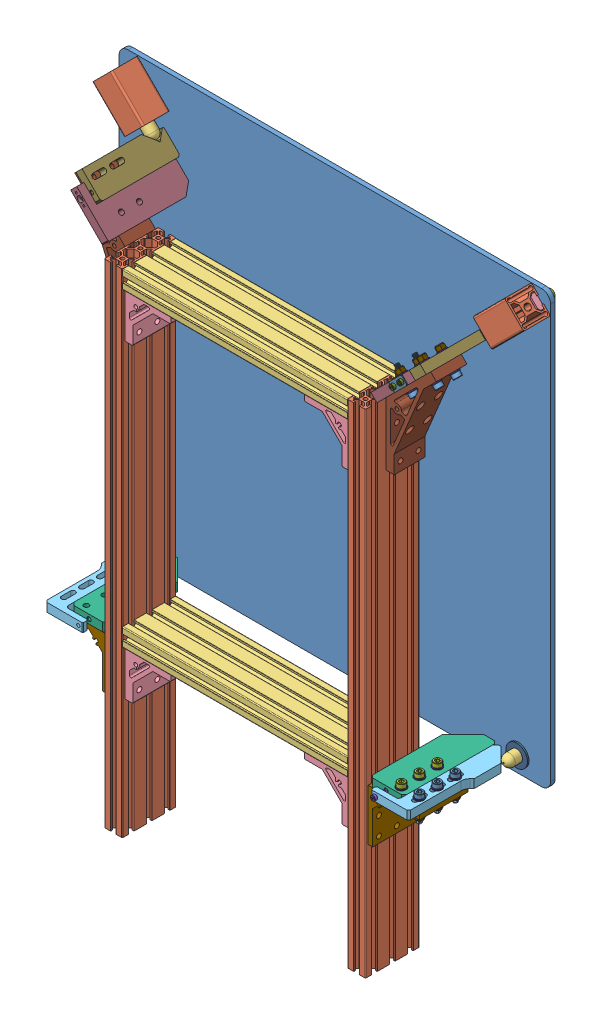
SolidWorks assembly Bed2-MountAssembly, configuration Default. Lengths in mm.
Overall size (480 651.24 139.8).
101 component instances, 28 part files, 132 mates.
Components (placement in the parent):
- Bed2-Assembly-1: Bed2-Assembly [Default] at origin size (480 480 46.46)
  - Bed2_5mm-1: Bed2_5mm [Default] at origin size (480 480 5)
  - HFS6_3030_50_LTP-1: HFS6_3030_50_LTP [Default] at (194.0381 194.0381 20) x (0.707107 -0.707107 0) z (-0.707107 -0.707107 0) size (30 30 50)
  - HFS6_3030_50_LTP-2: HFS6_3030_50_LTP [Default] at (-194.0381 194.0381 20) x (0.707107 0.707107 0) z (0.707107 -0.707107 0) size (30 30 50)
  - CJPQNBB8_13-1: CJPQNBB8_13 [Default] at (-194.0381 194.0381 20) x (0.707107 -0.707107 0) z (-0.707107 -0.707107 0) size (31.47 13 13)
  - CJPQNBB8_13-2: CJPQNBB8_13 [Default] at (194.0381 194.0381 20) x (-0.707107 -0.707107 0) z (0.707107 -0.707107 0) size (31.47 13 13)
  - HNTC6-1: HNTC6 [Default] at (-197.5736 197.5736 7) x (0.707107 0.707107 0) z (0 0 1) size (15 16 6.3)
  - HNTC6-2: HNTC6 [Default] at (-213.9106 213.9106 7) x (-0.707107 -0.707107 0) z (0 0 1) size (15 16 6.3)
  - HNTC6-3: HNTC6 [Default] at (-225.8579 225.8579 7) x (-0.707107 -0.707107 0) z (0 0 1) size (15 16 6.3)
  - HNTC6-4: HNTC6 [Default] at (213.9106 213.9106 7) x (-0.707107 0.707107 0) z (0 0 1) size (15 16 6.3)
  - HNTC6-5: HNTC6 [Default] at (197.5736 197.5736 7) x (0.707107 -0.707107 0) z (0 0 1) size (15 16 6.3)
  - HNTC6-6: HNTC6 [Default] at (225.8579 225.8579 7) x (-0.707107 0.707107 0) z (0 0 1) size (15 16 6.3)
  - 1-4_silicone_99604A115-1: 1-4_silicone_99604A115 [99604A115] at (-197.5736 197.5736 0) size (15.88 15.88 2.36)
  - 1-4_silicone_99604A115-2: 1-4_silicone_99604A115 [99604A115] at (225.8579 225.8579 0) size (15.88 15.88 2.36)
  - 1-4_silicone_99604A115-3: 1-4_silicone_99604A115 [99604A115] at (-225.8579 225.8579 0) size (15.88 15.88 2.36)
  - 1-4_silicone_99604A115-4: 1-4_silicone_99604A115 [99604A115] at (197.5736 197.5736 0) size (15.88 15.88 2.36)
  - 1-4_silicone_99604A115-5: 1-4_silicone_99604A115 [99604A115] at (213.9106 213.9106 0) size (15.88 15.88 2.36)
  - 1-4_silicone_99604A115-6: 1-4_silicone_99604A115 [99604A115] at (-213.9106 213.9106 0) size (15.88 15.88 2.36)
  - M6_ss_93475A250-1: M6_ss_93475A250 [93475A250] at (-197.5736 197.5736 -2.3622) size (12 12 1.4)
  - M6_ss_93475A250-2: M6_ss_93475A250 [93475A250] at (213.9106 213.9106 -2.3622) size (12 12 1.4)
  - M6_ss_93475A250-3: M6_ss_93475A250 [93475A250] at (-213.9106 213.9106 -2.3622) size (12 12 1.4)
  - M6_ss_93475A250-4: M6_ss_93475A250 [93475A250] at (197.5736 197.5736 -2.3622) size (12 12 1.4)
  - M6_ss_93475A250-5: M6_ss_93475A250 [93475A250] at (-225.8579 225.8579 -2.3622) size (12 12 1.4)
  - M6_ss_93475A250-6: M6_ss_93475A250 [93475A250] at (225.8579 225.8579 -2.3622) size (12 12 1.4)
  - M6x18_91292A136-1: M6x18_91292A136 [91292A136] at (-197.5736 197.5736 14.2378) size (10 10 24.53)
  - M6x18_91292A136-2: M6x18_91292A136 [91292A136] at (-213.9106 213.9106 14.2378) size (10 10 24.53)
  - M6x18_91292A136-3: M6x18_91292A136 [91292A136] at (-225.8579 225.8579 14.2378) size (10 10 24.53)
  - M6x18_91292A136-4: M6x18_91292A136 [91292A136] at (197.5736 197.5736 14.2378) size (10 10 24.53)
  - M6x18_91292A136-5: M6x18_91292A136 [91292A136] at (213.9106 213.9106 14.2378) size (10 10 24.53)
  - M6x18_91292A136-6: M6x18_91292A136 [91292A136] at (225.8579 225.8579 14.2378) size (10 10 24.53)
  - CJPQNBB8_13-3: CJPQNBB8_13 [Default] at (-204 -222 6.8) x (0 0 1) z (-0.99919 0.040233 0) size (31.47 13 13)
  - CJPQNBB8_13-4: CJPQNBB8_13 [Default] at (204 -222 6.8) x (0 0 1) z (-0.9546 0.297892 0) size (31.47 13 13)
  - 5-16_silicone_99604A119-1: 5-16_silicone_99604A119 [99604A119] at (-204 -222 0) size (17.46 17.46 2.36)
  - 5-16_silicone_99604A119-2: 5-16_silicone_99604A119 [99604A119] at (204 -222 0) size (17.46 17.46 2.36)
  - Nyloc_M8_flange_ss_92461A300-1: Nyloc_M8_flange_ss_92461A300 [92461A300] at (204 -222 -2.3622) x (1 0 0) z (0 1 0) size (14.2 9.28 14.2)
  - Nyloc_M8_flange_ss_92461A300-2: Nyloc_M8_flange_ss_92461A300 [92461A300] at (-204 -222 -2.3622) x (1 0 0) z (0 1 0) size (14.2 9.28 14.2)
  - M8_fender_ss_91116A160-1: M8_fender_ss_91116A160 [91116A160] at (204 -222 6.8) size (24 24 1.8)
  - M8_fender_ss_91116A160-2: M8_fender_ss_91116A160 [91116A160] at (-204 -222 6.8) size (24 24 1.8)
- HBL135TD5_Z5-1: HBL135TD5_Z5 [Default] at (145.2477 136.7624 76.1924) x (0 0 -1) z (0 -1 0) size (34 55.86 119.5)
  - HBL135TD5_Z5hbl45ts5-1: HBL135TD5_Z5hbl45ts5 [Default] at origin size (34 55.86 119.5)
- V-block_3-1: V-block_3 [Default] x (0 0 -1) z (0.707107 -0.707107 0) size (88.19 30 9.53)
- V-block_3-stage-1: V-block_3-stage [Default] at (3.5355 -3.5355 -1056) x (0 0 -1) z (0.707107 -0.707107 0) size (96.19 50 9.52)
- ScrewRetainer^Bed2-MountAssembly-1: ScrewRetainer^Bed2-MountAssembly [Default] at (0 0 89.1924) x (0.707107 -0.707107 0) z (0 0 1) size (9.53 20 1) (virtual)
- low_M3x20_92855A319-1: low_M3x20_92855A319 [92855A319] at (177.2354 175.4853 100.1924) x (-0.158388 0.987377 0) z (0 0 1) size (5.5 5.5 22.13)
- M3x4_91292A109-1: M3x4_91292A109 [91292A109] at (181.4781 179.728 108.1924) x (-0.923728 -0.383049 0) z (0 0 -1) size (5.5 5.5 7.14)
- M3x4_91292A109-2: M3x4_91292A109 [91292A109] at (172.9928 171.2427 108.1924) x (-0.923728 -0.383049 0) z (0 0 -1) size (5.5 5.5 7.14)
- M5_ss_93475A240-1: M5_ss_93475A240 [93475A240] at (180.3025 186.5604 86.1924) x (0.707107 0.707107 0) z (-0.707107 0.707107 0) size (10 10 0.9)
- M5_ss_93475A240-2: M5_ss_93475A240 [93475A240] at (155.5538 161.8117 86.1924) x (0.707107 0.707107 0) z (-0.707107 0.707107 0) size (10 10 0.9)
- M5_ss_93475A240-3: M5_ss_93475A240 [93475A240] at (155.5538 161.8117 66.1924) x (0.707107 0.707107 0) z (-0.707107 0.707107 0) size (10 10 0.9)
- M5_ss_93475A240-4: M5_ss_93475A240 [93475A240] at (180.3025 186.5604 66.1924) x (0.707107 0.707107 0) z (-0.707107 0.707107 0) size (10 10 0.9)
- M5_ss_93475A240-5: M5_ss_93475A240 [93475A240] at (167.0973 150.2681 66.1924) x (0.707107 0.707107 0) z (0.707107 -0.707107 0) size (10 10 0.9)
- M5_ss_93475A240-6: M5_ss_93475A240 [93475A240] at (194.6745 172.1885 86.1924) x (0.7071 0.7071 0.004344) z (0.707107 -0.707107 0) size (10 10 0.9)
- M5_ss_93475A240-7: M5_ss_93475A240 [93475A240] at (194.6745 172.1885 66.1924) x (0.707107 0.707107 0) z (0.707107 -0.707107 0) size (10 10 0.9)
- M5_ss_93475A240-8: M5_ss_93475A240 [93475A240] at (167.0973 150.2681 86.1924) x (0.707107 0.707107 0) z (0.707107 -0.707107 0) size (10 10 0.9)
- Nyloc_M5_90576A104-1: Nyloc_M5_90576A104 [90576A104] at (155.5538 161.8117 66.1924) x (0.707107 0.707107 0) z (0 0 1) size (8 5.15 9.24)
- Nyloc_M5_90576A104-2: Nyloc_M5_90576A104 [90576A104] at (180.3025 186.5604 66.1924) x (0.707107 0.707107 0) z (0 0 1) size (8 5.15 9.24)
- Nyloc_M5_90576A104-3: Nyloc_M5_90576A104 [90576A104] at (155.5538 161.8117 86.1924) x (0.707107 0.707107 0) z (0 0 1) size (8 5.15 9.24)
- Nyloc_M5_90576A104-4: Nyloc_M5_90576A104 [90576A104] at (180.3025 186.5604 86.1924) x (0.707107 0.707107 0) z (0 0 1) size (8 5.15 9.24)
- M5x25_91292A129-1: M5x25_91292A129 [91292A129] at (176.9968 189.8661 86.1924) x (0.224391 0.224391 0.948313) z (-0.707107 0.707107 0) size (8.5 8.5 30.44)
- M5x25_91292A129-2: M5x25_91292A129 [91292A129] at (176.9968 189.8661 66.1924) x (0.5 0.5 0.707107) z (-0.707107 0.707107 0) size (8.5 8.5 30.44)
- M5x25_91292A129-3: M5x25_91292A129 [91292A129] at (149.4196 167.9458 86.1924) x (0.5 0.5 0.707107) z (-0.707107 0.707107 0) size (8.5 8.5 30.44)
- M5x25_91292A129-4: M5x25_91292A129 [91292A129] at (149.4196 167.9458 66.1924) x (0.5 0.5 0.707107) z (-0.707107 0.707107 0) size (8.5 8.5 30.44)
- StructuralFrame-1^Bed2-MountAssembly-1: StructuralFrame-1^Bed2-MountAssembly [Default<As Machined>] at (0 0 54.1924) size (290.5 548 60) (virtual)
- HBL135TD5_Z5-2: HBL135TD5_Z5 [Default] at (-145.2477 136.7624 76.1924) x (0 0 1) z (0 -1 0) size (34 55.86 119.5)
  - HBL135TD5_Z5hbl45ts5-1: HBL135TD5_Z5hbl45ts5 [Default] at origin size (34 55.86 119.5)
- V-block_3-2: V-block_3 [Default] at (-1.7501 -1.7501 0) x (0 0 -1) z (0.707107 0.707107 0) size (88.19 30 9.53)
- V-block_3-stage-2: V-block_3-stage [Default] at (1.7854 1.7854 -1056) x (0 0 -1) z (0.707107 0.707107 0) size (96.19 50 9.52)
- StructuralFrame-2^Bed2-MountAssembly-1: StructuralFrame-2^Bed2-MountAssembly [Default<As Machined>] at (0 -0.0245 76.1924) size (250.5 364.69 60) (virtual)
- HBLUT5-1: HBLUT5 [Default] at (125.2477 116.7624 86.1924) x (0 0 1) z (0 -1 0) size (54 51 51)
- HBLUT5-2: HBLUT5 [Default] at (-125.2477 116.7624 86.1924) x (0 0 1) z (1 0 0) size (54 51 51)
- HBLUT5-3: HBLUT5 [Default] at (-125.2477 -227.9285 86.1924) x (0 0 -1) z (0 -1 0) size (54 51 51)
- HBLUT5-4: HBLUT5 [Default] at (125.2477 -227.9285 86.1924) x (0 0 1) z (0 -1 0) size (54 51 51)
- V-block_4-1: V-block_4 [Default] at (0 -222 0) x (-1 0 0) z (0 1 0) size (47.16 113.8 9.53)
- V-block_4-stage-1: V-block_4-stage [Default] at (0 -222 0) x (-1 0 0) z (0 1 0) size (38 103.64 9.53)
- M5_ss_93475A240-9: M5_ss_93475A240 [93475A240] at (175.2477 -217.2375 66.1924) x (1 0 0) z (0 -1 0) size (10 10 0.9)
- M5_ss_93475A240-10: M5_ss_93475A240 [93475A240] at (175.2477 -217.2375 106.1924) x (1 0 0) z (0 -1 0) size (10 10 0.9)
- M5_ss_93475A240-11: M5_ss_93475A240 [93475A240] at (175.2477 -217.2375 86.1924) x (1 0 0) z (0 -1 0) size (10 10 0.9)
- M5_ss_93475A240-12: M5_ss_93475A240 [93475A240] at (195.2477 -217.2375 106.1924) x (1 0 0) z (0 -1 0) size (10 10 0.9)
- M5_ss_93475A240-13: M5_ss_93475A240 [93475A240] at (195.2477 -217.2375 66.1924) x (1 0 0) z (0 -1 0) size (10 10 0.9)
- M5_ss_93475A240-14: M5_ss_93475A240 [93475A240] at (195.2477 -217.2375 86.1924) x (1 0 0) z (0 -1 0) size (10 10 0.9)
- M5_ss_93475A240-15: M5_ss_93475A240 [93475A240] at (195.2477 -232.6625 106.1924) x (-0.837169 0 -0.546944) z (0 -1 0) size (10 10 0.9)
- M5_ss_93475A240-16: M5_ss_93475A240 [93475A240] at (195.2477 -232.6625 86.1924) x (0.837169 0 0.546944) z (0 -1 0) size (10 10 0.9)
- M5_ss_93475A240-17: M5_ss_93475A240 [93475A240] at (195.2477 -232.6625 66.1924) x (0.837169 0 0.546944) z (0 -1 0) size (10 10 0.9)
- Nyloc_M5_90576A104-5: Nyloc_M5_90576A104 [90576A104] at (195.2477 -232.6625 106.1924) x (0.837169 0 0.546944) z (0.546944 0 -0.837169) size (8 5.15 9.24)
- Nyloc_M5_90576A104-6: Nyloc_M5_90576A104 [90576A104] at (195.2477 -232.6625 86.1924) x (-0.837169 0 -0.546944) z (-0.546944 0 0.837169) size (8 5.15 9.24)
- Nyloc_M5_90576A104-7: Nyloc_M5_90576A104 [90576A104] at (195.2477 -232.6625 66.1924) x (-0.837169 0 -0.546944) z (-0.546944 0 0.837169) size (8 5.15 9.24)
- M5x25_91292A129-5: M5x25_91292A129 [91292A129] at (195.2477 -241.3375 106.1924) x (1 0 0) z (0 -1 0) size (8.5 8.5 30.44)
- M5x25_91292A129-6: M5x25_91292A129 [91292A129] at (195.2477 -241.3375 86.1924) x (1 0 0) z (0 -1 0) size (8.5 8.5 30.44)
- M5x25_91292A129-7: M5x25_91292A129 [91292A129] at (195.2477 -241.3375 66.1924) x (1 0 0) z (0 -1 0) size (8.5 8.5 30.44)
- M5x20_91292A128-1: M5x20_91292A128 [91292A128] at (175.2477 -236.3375 106.1924) x (-0.187372 0 -0.982289) z (0 -1 0) size (8.5 8.5 25.41)
- M5x20_91292A128-2: M5x20_91292A128 [91292A128] at (175.2477 -236.3375 86.1924) x (-0.992424 0 0.122859) z (0 -1 0) size (8.5 8.5 25.41)
- M5x20_91292A128-3: M5x20_91292A128 [91292A128] at (175.2477 -236.3375 66.1924) x (1 0 0) z (0 -1 0) size (8.5 8.5 25.41)
- M3x25_91292A020-1: M3x25_91292A020 [91292A020] at (165.2477 -222 100.1924) x (-0.923728 -0.383049 0) z (0 0 -1) size (5.5 5.5 28.2)
- V-block_4-2: V-block_4 [Default] at (0 -222 0) x (1 0 0) z (0 -1 0) size (47.16 113.8 9.53)
- V-block_4-stage-2: V-block_4-stage [Default] at (0 -222 0) x (1 0 0) z (0 -1 0) size (38 103.64 9.53)
- KH-808-1: KH-808 [Default] at (104.8903 88.2954 5.1) size (203.2 203.2 0.1) (hidden)
- KH-808-2: KH-808 [Default] at (-100.6787 87.2584 5.1) size (203.2 203.2 0.1) (hidden)
- KH-808-3: KH-808 [Default] at (103.99 -116.6795 5.1) size (203.2 203.2 0.1) (hidden)
- KH-808-4: KH-808 [Default] at (-99.4131 -117.1513 5.1) size (203.2 203.2 0.1) (hidden)
- HBLTTW5-1: HBLTTW5 [Default] at (157.2477 -238.7625 86.1924) x (0 1 0) z (0 0 -1) size (57 57 54)
- HBLTTW5-2: HBLTTW5 [Default] at (-157.2477 -238.7625 86.1924) x (0 1 0) z (0 0 1) size (57 57 54)
Mates (geometry in assembly coordinates):
- Coincident1: coincident aligned: plane of Bed2-Assembly-1/Bed2_5mm-1 through (0 0 0) normal (0 0 1); plane of assembly through (0 0 0) normal (0 0 1)
- Coincident2: coincident aligned: plane of Bed2-Assembly-1/Bed2_5mm-1 through (0 0 0) normal (0 1 0); plane of assembly through (0 0 0) normal (0 1 0)
- Coincident3: coincident aligned: plane of Bed2-Assembly-1/Bed2_5mm-1 through (0 0 0) normal (1 0 0); plane of assembly through (0 0 0) normal (1 0 0)
- Coincident14: coincident anti-aligned: plane of HBL135TD5_Z5-1/HBL135TD5_Z5hbl45ts5-1 through (145.2477 136.7624 59.1924) normal (-0.707107 0.707107 0); plane of V-block_3-1 through (187.1845 178.6992 20) normal (0.707107 -0.707107 0)
- Coincident22: coincident aligned: plane of M3x4_91292A109-1 through (181.4781 179.728 112.1924) normal (0 0 -1); plane of M3x4_91292A109-2 through (172.9928 171.2427 112.1924) normal (0 0 -1)
- Coincident23: coincident anti-aligned: plane of ScrewRetainer^Bed2-MountAssembly-1 through (166.7968 171.7819 112.1924) normal (0 0 1); plane of M3x4_91292A109-1 through (181.4781 179.728 112.1924) normal (0 0 -1)
- Concentric1: concentric aligned: cylinder of ScrewRetainer^Bed2-MountAssembly-1 through (181.4781 179.728 112.1924) axis (0 0 -1) radius 1.75; cylinder of M3x4_91292A109-1 through (181.4781 179.728 115.1924) axis (0 0 -1) radius 2.75
- Concentric2: concentric aligned: cylinder of ScrewRetainer^Bed2-MountAssembly-1 through (172.9928 171.2427 112.1924) axis (0 0 -1) radius 1.75; cylinder of M3x4_91292A109-2 through (172.9928 171.2427 115.1924) axis (0 0 -1) radius 2.75
- Concentric3: concentric anti-aligned: cylinder of V-block_3-stage-1 through (177.2354 175.4853 15) axis (0 0 1) radius 1.7; cylinder of low_M3x20_92855A319-1 through (177.2354 175.4853 100.1924) axis (0 0 -1) radius 1.5
- Coincident25: coincident aligned: plane of M5_ss_93475A240-1 through (180.3025 186.5604 86.1924) normal (-0.707107 0.707107 0); plane of M5_ss_93475A240-3 through (155.5538 161.8117 66.1924) normal (-0.707107 0.707107 0)
- Coincident26: coincident aligned: plane of M5_ss_93475A240-1 through (180.3025 186.5604 86.1924) normal (-0.707107 0.707107 0); plane of M5_ss_93475A240-2 through (155.5538 161.8117 86.1924) normal (-0.707107 0.707107 0)
- Coincident27: coincident aligned: plane of M5_ss_93475A240-1 through (180.3025 186.5604 86.1924) normal (-0.707107 0.707107 0); plane of M5_ss_93475A240-4 through (180.3025 186.5604 66.1924) normal (-0.707107 0.707107 0)
- Coincident30: coincident aligned: plane of M5_ss_93475A240-5 through (167.0973 150.2681 66.1924) normal (0.707107 -0.707107 0); plane of M5_ss_93475A240-8 through (167.0973 150.2681 86.1924) normal (0.707107 -0.707107 0)
- Coincident31: coincident aligned: plane of Nyloc_M5_90576A104-1 through (158.3822 164.6401 63.883) normal (0.707107 -0.707107 0); plane of Nyloc_M5_90576A104-2 through (183.1309 189.3888 63.883) normal (0.707107 -0.707107 0)
- Coincident32: coincident aligned: plane of Nyloc_M5_90576A104-1 through (158.3822 164.6401 63.883) normal (0.707107 -0.707107 0); plane of Nyloc_M5_90576A104-4 through (183.1309 189.3888 83.883) normal (0.707107 -0.707107 0)
- Coincident33: coincident aligned: plane of Nyloc_M5_90576A104-1 through (158.3822 164.6401 63.883) normal (0.707107 -0.707107 0); plane of Nyloc_M5_90576A104-3 through (158.3822 164.6401 83.883) normal (0.707107 -0.707107 0)
- Coincident34: coincident anti-aligned: plane of M5_ss_93475A240-1 through (180.3025 186.5604 86.1924) normal (-0.707107 0.707107 0); plane of Nyloc_M5_90576A104-1 through (158.3822 164.6401 63.883) normal (0.707107 -0.707107 0)
- Concentric4: concentric anti-aligned: cylinder of M5_ss_93475A240-3 through (156.1902 161.1753 66.1924) axis (-0.707107 0.707107 0) radius 5; cylinder of Nyloc_M5_90576A104-1 through (152.5536 164.8118 66.1924) axis (0.707107 -0.707107 0) radius 2.1277
- Concentric5: concentric anti-aligned: cylinder of M5_ss_93475A240-1 through (180.9389 185.924 86.1924) axis (-0.707107 0.707107 0) radius 2.65; cylinder of Nyloc_M5_90576A104-4 through (177.3024 189.5606 86.1924) axis (0.707107 -0.707107 0) radius 2.1277
- Concentric6: concentric anti-aligned: cylinder of M5_ss_93475A240-2 through (156.1902 161.1753 86.1924) axis (-0.707107 0.707107 0) radius 2.65; cylinder of Nyloc_M5_90576A104-3 through (152.5536 164.8118 86.1924) axis (0.707107 -0.707107 0) radius 2.1277
- Concentric7: concentric anti-aligned: cylinder of M5_ss_93475A240-4 through (180.9389 185.924 66.1924) axis (-0.707107 0.707107 0) radius 2.65; cylinder of Nyloc_M5_90576A104-2 through (177.3024 189.5606 66.1924) axis (0.707107 -0.707107 0) radius 2.1277
- Concentric8: concentric anti-aligned: cylinder of M5_ss_93475A240-3 through (156.1902 161.1753 66.1924) axis (-0.707107 0.707107 0) radius 5; cylinder of M5_ss_93475A240-5 through (166.4609 150.9045 66.1924) axis (0.707107 -0.707107 0) radius 5
- Concentric9: concentric anti-aligned: cylinder of M5_ss_93475A240-1 through (180.9389 185.924 86.1924) axis (-0.707107 0.707107 0) radius 5; cylinder of M5_ss_93475A240-6 through (194.0381 172.8249 86.1924) axis (0.707107 -0.707107 0) radius 5
- Concentric10: concentric anti-aligned: cylinder of M5_ss_93475A240-2 through (156.1902 161.1753 86.1924) axis (-0.707107 0.707107 0) radius 5; cylinder of M5_ss_93475A240-8 through (166.4609 150.9045 86.1924) axis (0.707107 -0.707107 0) radius 5
- Concentric11: concentric anti-aligned: cylinder of M5_ss_93475A240-4 through (180.9389 185.924 66.1924) axis (-0.707107 0.707107 0) radius 5; cylinder of M5_ss_93475A240-7 through (194.0381 172.8249 66.1924) axis (0.707107 -0.707107 0) radius 5
- Coincident35: coincident anti-aligned: plane of V-block_3-stage-1 through (180.4493 185.4344 20) normal (-0.707107 0.707107 0); plane of M5_ss_93475A240-3 through (156.1902 161.1753 66.1924) normal (0.707107 -0.707107 0)
- Coincident36: coincident anti-aligned: plane of HBL135TD5_Z5-1/HBL135TD5_Z5hbl45ts5-1 through (154.8777 139.3213 59.1924) normal (0.707107 -0.707107 0); plane of M5_ss_93475A240-8 through (166.4609 150.9045 86.1924) normal (-0.707107 0.707107 0)
- Coincident37: coincident aligned: plane of M5_ss_93475A240-6 through (194.0381 172.8249 86.1924) normal (-0.707107 0.707107 0); plane of M5_ss_93475A240-7 through (194.0381 172.8249 66.1924) normal (-0.707107 0.707107 0)
- Coincident38: coincident anti-aligned: plane of HBL135TD5_Z5-1/HBL135TD5_Z5hbl45ts5-1 through (201.1091 179.8959 59.1924) normal (0.707107 -0.707107 0); plane of M5_ss_93475A240-6 through (194.0381 172.8249 86.1924) normal (-0.707107 0.707107 0)
- Concentric15: concentric anti-aligned: cylinder of HBL135TD5_Z5-1/HBL135TD5_Z5hbl45ts5-1 through (187.6741 179.1888 86.1924) axis (0.707107 -0.707107 0) radius 2.75; cylinder of M5_ss_93475A240-1 through (180.9389 185.924 86.1924) axis (-0.707107 0.707107 0) radius 5
- Concentric16: concentric anti-aligned: cylinder of HBL135TD5_Z5-1/HBL135TD5_Z5hbl45ts5-1 through (187.6741 179.1888 66.1924) axis (0.707107 -0.707107 0) radius 2.75; cylinder of M5_ss_93475A240-4 through (180.9389 185.924 66.1924) axis (-0.707107 0.707107 0) radius 5
- Coincident41: coincident aligned: plane of M5x25_91292A129-1 through (194.6745 172.1885 86.1924) normal (-0.707107 0.707107 0); plane of M5x25_91292A129-2 through (194.6745 172.1885 66.1924) normal (-0.707107 0.707107 0)
- Coincident42: coincident aligned: plane of M5x25_91292A129-3 through (167.0973 150.2681 86.1924) normal (-0.707107 0.707107 0); plane of M5x25_91292A129-4 through (167.0973 150.2681 66.1924) normal (-0.707107 0.707107 0)
- Coincident43: coincident anti-aligned: plane of M5_ss_93475A240-6 through (194.6745 172.1885 86.1924) normal (0.707107 -0.707107 0); plane of M5x25_91292A129-1 through (194.6745 172.1885 86.1924) normal (-0.707107 0.707107 0)
- Coincident44: coincident anti-aligned: plane of M5_ss_93475A240-8 through (167.0973 150.2681 86.1924) normal (0.707107 -0.707107 0); plane of M5x25_91292A129-3 through (167.0973 150.2681 86.1924) normal (-0.707107 0.707107 0)
- Concentric17: concentric anti-aligned: cylinder of M5_ss_93475A240-5 through (166.4609 150.9045 66.1924) axis (0.707107 -0.707107 0) radius 2.65; cylinder of M5x25_91292A129-4 through (170.6328 146.7326 66.1924) axis (-0.707107 0.707107 0) radius 4.25
- Concentric18: concentric anti-aligned: cylinder of M5_ss_93475A240-8 through (166.4609 150.9045 86.1924) axis (0.707107 -0.707107 0) radius 2.65; cylinder of M5x25_91292A129-3 through (170.6328 146.7326 86.1924) axis (-0.707107 0.707107 0) radius 4.25
- Concentric19: concentric anti-aligned: cylinder of M5_ss_93475A240-6 through (194.0381 172.8249 86.1924) axis (0.707107 -0.707107 0) radius 2.65; cylinder of M5x25_91292A129-1 through (198.21 168.6529 86.1924) axis (-0.707107 0.707107 0) radius 4.25
- Concentric20: concentric anti-aligned: cylinder of M5_ss_93475A240-7 through (194.0381 172.8249 66.1924) axis (0.707107 -0.707107 0) radius 2.65; cylinder of M5x25_91292A129-2 through (198.21 168.6529 66.1924) axis (-0.707107 0.707107 0) radius 4.25
- Coincident48: coincident aligned: plane of HBL135TD5_Z5-1/HBL135TD5_Z5hbl45ts5-1 through (145.2477 66.7624 59.1924) normal (0 0 -1); plane of HBL135TD5_Z5-2/HBL135TD5_Z5hbl45ts5-1 through (-145.2477 66.7624 59.1924) normal (0 0 -1)
- Coincident49: coincident: plane of HBL135TD5_Z5-2/HBL135TD5_Z5hbl45ts5-1 through (-145.2477 66.7624 93.1924) normal (1 0 0); line of assembly
- Coincident50: coincident: plane of HBL135TD5_Z5-2/HBL135TD5_Z5hbl45ts5-1 through (-145.2477 136.7624 93.1924) normal (0.707107 0.707107 0); line of assembly
- Coincident51: coincident anti-aligned: plane of HBL135TD5_Z5-2/HBL135TD5_Z5hbl45ts5-1 through (-145.2477 136.7624 93.1924) normal (0.707107 0.707107 0); plane of V-block_3-stage-2 through (-187.1845 178.6992 20) normal (-0.707107 -0.707107 0)
- Concentric21: concentric anti-aligned: cylinder of HBL135TD5_Z5-2/HBL135TD5_Z5hbl45ts5-1 through (-184.1386 133.2269 66.1924) axis (0.707107 0.707107 0) radius 2.75; cylinder of V-block_3-stage-2 through (-79.5319 237.8335 66.1924) axis (-0.707107 -0.707107 0) radius 2.75
- Concentric22: concentric anti-aligned: cylinder of HBL135TD5_Z5-2/HBL135TD5_Z5hbl45ts5-1 through (-184.1386 133.2269 86.1924) axis (0.707107 0.707107 0) radius 2.75; cylinder of V-block_3-stage-2 through (-79.5319 237.8335 86.1924) axis (-0.707107 -0.707107 0) radius 2.75
- Coincident52: coincident anti-aligned: plane of HBL135TD5_Z5-2/HBL135TD5_Z5hbl45ts5-1 through (-145.2477 136.7624 93.1924) normal (0.707107 0.707107 0); plane of V-block_3-2 through (-187.1845 178.6992 20) normal (-0.707107 -0.707107 0)
- Parallel1: parallel anti-aligned: plane of V-block_3-2 through (-173.532 165.0467 10) normal (0.707107 -0.707107 0); plane of V-block_3-stage-2 through (-90.1385 248.4401 15) normal (-0.707107 0.707107 0)
- Tangent2: tangent anti-aligned: sphere of Bed2-Assembly-1/CJPQNBB8_13-1; plane of V-block_3-2 through (-193.1949 184.7096 10) normal (-0.5 0.5 0.707107)
- Tangent3: tangent anti-aligned: sphere of Bed2-Assembly-1/CJPQNBB8_13-1; plane of V-block_3-2 through (-194.7452 186.2599 32.1924) normal (-0.5 0.5 -0.707107)
- Coincident54: coincident aligned: plane of HBL135TD5_Z5-1/HBL135TD5_Z5hbl45ts5-1 through (194.7452 186.2599 59.1924) normal (0.707107 0.707107 0); plane of V-block_3-1 through (188.01 192.9951 98.1924) normal (0.707107 0.707107 0)
- Coincident61: coincident anti-aligned: plane of StructuralFrame-2^Bed2-MountAssembly-1 through (-125 116.7624 89.4924) normal (0 -1 0); plane of HBLUT5-1 through (124.2477 116.7624 113.1924) normal (0 1 0)
- Coincident62: coincident anti-aligned: plane of StructuralFrame-1^Bed2-MountAssembly-1 through (125.2477 -411.2376 82.8924) normal (-1 0 0); plane of HBLUT5-1 through (125.2477 66.7624 113.1924) normal (1 0 0)
- Coincident63: coincident anti-aligned: plane of StructuralFrame-2^Bed2-MountAssembly-1 through (-125 116.7624 89.4924) normal (0 -1 0); plane of HBLUT5-2 through (-75.2477 116.7624 113.1924) normal (0 1 0)
- Coincident64: coincident anti-aligned: plane of StructuralFrame-1^Bed2-MountAssembly-1 through (-125.2477 -411.2376 89.4924) normal (1 0 0); plane of HBLUT5-2 through (-125.2477 115.7624 113.1924) normal (-1 0 0)
- Coincident65: coincident aligned: plane of HBLUT5-1 through (124.2477 66.7624 113.1924) normal (0 0 1); plane of HBLUT5-2 through (-75.2477 115.7624 113.1924) normal (0 0 1)
- Coincident66: coincident anti-aligned: plane of StructuralFrame-1^Bed2-MountAssembly-1 through (125.2477 -411.2376 102.8924) normal (-1 0 0); plane of HBLUT5-4 through (125.2477 -277.9285 113.1924) normal (1 0 0)
- Coincident67: coincident anti-aligned: plane of StructuralFrame-2^Bed2-MountAssembly-1 through (-125.2477 -227.9285 89.4924) normal (0 -1 0); plane of HBLUT5-4 through (124.2477 -227.9285 113.1924) normal (0 1 0)
- Coincident68: coincident anti-aligned: plane of StructuralFrame-1^Bed2-MountAssembly-1 through (-125.2477 -411.2376 89.4924) normal (1 0 0); plane of HBLUT5-3 through (-125.2477 -277.9285 59.1924) normal (-1 0 0)
- Coincident69: coincident anti-aligned: plane of StructuralFrame-2^Bed2-MountAssembly-1 through (-125.2477 -227.9285 89.4924) normal (0 -1 0); plane of HBLUT5-3 through (-124.2477 -227.9285 59.1924) normal (0 1 0)
- Coincident70: coincident aligned: plane of HBLUT5-3 through (-124.2477 -277.9285 113.1924) normal (0 0 1); plane of HBLUT5-4 through (124.2477 -277.9285 113.1924) normal (0 0 1)
- Coincident71: coincident aligned: plane of StructuralFrame-1^Bed2-MountAssembly-1 through (0 0 86.1924) normal (0 0 1); plane of HBLUT5-1
- Coincident72: coincident aligned: plane of HBLUT5-2 through (-75.2477 115.7624 113.1924) normal (0 0 1); plane of HBLUT5-3 through (-124.2477 -277.9285 113.1924) normal (0 0 1)
- InPlace7: in place: plane of ? through (0 -222 0) normal (0 1 0); moOrthogonalPlaneRef_w of ?; line of ? through (-55 0 -222) axis (0 -1 0); unknown of ?
- Coincident77: coincident aligned: plane of V-block_4-1; plane of assembly
- Coincident78: coincident aligned: unknown of ?
- Coincident79: coincident anti-aligned: line of ? through (-62.5879 0 -222) axis (0 -1 0)
- InPlace8: in place: plane of ? through (0 -222 0) normal (0 1 0); unknown of ?; line of ? through (-55 0 -222) axis (0 -1 0); unknown of ?
- Coincident77: coincident aligned: plane of V-block_4-stage-1; plane of assembly
- Coincident78: coincident aligned: unknown of ?
- Coincident79: coincident anti-aligned: line of ? through (-57.002 0 -222) axis (0 -1 0)
- Coincident82: coincident aligned: plane of M5_ss_93475A240-9 through (175.2477 -217.2375 66.1924) normal (0 -1 0); plane of M5_ss_93475A240-11 through (175.2477 -217.2375 86.1924) normal (0 -1 0)
- Coincident83: coincident aligned: plane of M5_ss_93475A240-9 through (175.2477 -217.2375 66.1924) normal (0 -1 0); plane of M5_ss_93475A240-10 through (175.2477 -217.2375 106.1924) normal (0 -1 0)
- Coincident84: coincident aligned: plane of M5_ss_93475A240-12 through (195.2477 -217.2375 106.1924) normal (0 -1 0); plane of M5_ss_93475A240-14 through (195.2477 -217.2375 86.1924) normal (0 -1 0)
- Coincident85: coincident aligned: plane of M5_ss_93475A240-12 through (195.2477 -217.2375 106.1924) normal (0 -1 0); plane of M5_ss_93475A240-13 through (195.2477 -217.2375 66.1924) normal (0 -1 0)
- Coincident86: coincident aligned: plane of M5_ss_93475A240-15 through (195.2477 -232.6625 106.1924) normal (0 -1 0); plane of M5_ss_93475A240-16 through (195.2477 -232.6625 86.1924) normal (0 -1 0)
- Coincident87: coincident aligned: plane of M5_ss_93475A240-15 through (195.2477 -232.6625 106.1924) normal (0 -1 0); plane of M5_ss_93475A240-17 through (195.2477 -232.6625 66.1924) normal (0 -1 0)
- Coincident88: coincident aligned: plane of Nyloc_M5_90576A104-5 through (197.3333 -232.6625 110.3135) normal (0 1 0); plane of Nyloc_M5_90576A104-6 through (193.1621 -232.6625 82.0713) normal (0 1 0)
- Coincident89: coincident aligned: plane of Nyloc_M5_90576A104-5 through (197.3333 -232.6625 110.3135) normal (0 1 0); plane of Nyloc_M5_90576A104-7 through (193.1621 -232.6625 62.0713) normal (0 1 0)
- Coincident90: coincident anti-aligned: plane of M5_ss_93475A240-15 through (195.2477 -232.6625 106.1924) normal (0 -1 0); plane of Nyloc_M5_90576A104-5 through (197.3333 -232.6625 110.3135) normal (0 1 0)
- Concentric24: concentric anti-aligned: cylinder of M5_ss_93475A240-15 through (195.2477 -231.7625 106.1924) axis (0 -1 0) radius 5; cylinder of Nyloc_M5_90576A104-5 through (195.2477 -236.9054 106.1924) axis (0 1 0) radius 2.1277
- Concentric25: concentric anti-aligned: cylinder of M5_ss_93475A240-16 through (195.2477 -231.7625 86.1924) axis (0 -1 0) radius 2.65; cylinder of Nyloc_M5_90576A104-6 through (195.2477 -236.9054 86.1924) axis (0 1 0) radius 2.1277
- Concentric26: concentric anti-aligned: cylinder of M5_ss_93475A240-17 through (195.2477 -231.7625 66.1924) axis (0 -1 0) radius 2.65; cylinder of Nyloc_M5_90576A104-7 through (195.2477 -236.9054 66.1924) axis (0 1 0) radius 2.1277
- Coincident91: coincident anti-aligned: plane of V-block_4-1 through (185.2477 -217.2375 11.3962) normal (0 1 0); plane of M5_ss_93475A240-12 through (195.2477 -217.2375 106.1924) normal (0 -1 0)
- Coincident92: coincident anti-aligned: plane of V-block_4-stage-1 through (170.2477 -217.2375 9.5523) normal (0 1 0); plane of M5_ss_93475A240-9 through (175.2477 -217.2375 66.1924) normal (0 -1 0)
- Concentric30: concentric aligned: cylinder of M5_ss_93475A240-13 through (195.2477 -216.3375 66.1924) axis (0 -1 0) radius 5; cylinder of M5_ss_93475A240-17 through (195.2477 -231.7625 66.1924) axis (0 -1 0) radius 5
- Concentric31: concentric aligned: cylinder of M5_ss_93475A240-14 through (195.2477 -216.3375 86.1924) axis (0 -1 0) radius 5; cylinder of M5_ss_93475A240-16 through (195.2477 -231.7625 86.1924) axis (0 -1 0) radius 5
- Concentric32: concentric aligned: cylinder of M5_ss_93475A240-12 through (195.2477 -216.3375 106.1924) axis (0 -1 0) radius 5; cylinder of M5_ss_93475A240-15 through (195.2477 -231.7625 106.1924) axis (0 -1 0) radius 5
- Concentric33: concentric anti-aligned: cylinder of V-block_4-stage-1 through (175.2477 -226.7625 106.1924) axis (0 1 0) radius 2.75; cylinder of M5_ss_93475A240-10 through (175.2477 -216.3375 106.1924) axis (0 -1 0) radius 5
- Concentric34: concentric anti-aligned: cylinder of V-block_4-stage-1 through (175.2477 -226.7625 66.1924) axis (0 1 0) radius 2.75; cylinder of M5_ss_93475A240-9 through (175.2477 -216.3375 66.1924) axis (0 -1 0) radius 5
- Concentric35: concentric anti-aligned: cylinder of V-block_4-stage-1 through (175.2477 -226.7625 86.1924) axis (0 1 0) radius 2.75; cylinder of M5_ss_93475A240-11 through (175.2477 -216.3375 86.1924) axis (0 -1 0) radius 5
- Coincident95: coincident aligned: plane of M5x25_91292A129-5 through (195.2477 -216.3375 106.1924) normal (0 -1 0); plane of M5x25_91292A129-6 through (195.2477 -216.3375 86.1924) normal (0 -1 0)
- Coincident96: coincident aligned: plane of M5x25_91292A129-5 through (195.2477 -216.3375 106.1924) normal (0 -1 0); plane of M5x25_91292A129-7 through (195.2477 -216.3375 66.1924) normal (0 -1 0)
- Coincident97: coincident anti-aligned: plane of M5_ss_93475A240-12 through (195.2477 -216.3375 106.1924) normal (0 1 0); plane of M5x25_91292A129-5 through (195.2477 -216.3375 106.1924) normal (0 -1 0)
- Concentric36: concentric aligned: cylinder of M5_ss_93475A240-12 through (195.2477 -216.3375 106.1924) axis (0 -1 0) radius 5; cylinder of M5x25_91292A129-5 through (195.2477 -211.3375 106.1924) axis (0 -1 0) radius 4.25
- Concentric37: concentric aligned: cylinder of M5_ss_93475A240-14 through (195.2477 -216.3375 86.1924) axis (0 -1 0) radius 5; cylinder of M5x25_91292A129-6 through (195.2477 -211.3375 86.1924) axis (0 -1 0) radius 4.25
- Concentric38: concentric aligned: cylinder of M5_ss_93475A240-13 through (195.2477 -216.3375 66.1924) axis (0 -1 0) radius 5; cylinder of M5x25_91292A129-7 through (195.2477 -211.3375 66.1924) axis (0 -1 0) radius 4.25
- Coincident98: coincident aligned: plane of M5x20_91292A128-1 through (175.2477 -216.3375 106.1924) normal (0 -1 0); plane of M5x20_91292A128-2 through (175.2477 -216.3375 86.1924) normal (0 -1 0)
- Coincident100: coincident aligned: plane of M5x20_91292A128-1 through (175.2477 -216.3375 106.1924) normal (0 -1 0); plane of M5x20_91292A128-3 through (175.2477 -216.3375 66.1924) normal (0 -1 0)
- Coincident101: coincident anti-aligned: plane of M5_ss_93475A240-10 through (175.2477 -216.3375 106.1924) normal (0 1 0); plane of M5x20_91292A128-1 through (175.2477 -216.3375 106.1924) normal (0 -1 0)
- Concentric43: concentric anti-aligned: cylinder of V-block_4-1 through (165.2477 -222 11.3962) axis (0 0 1) radius 1.75; cylinder of M3x25_91292A020-1 through (165.2477 -222 100.1924) axis (0 0 -1) radius 1.627
- Coincident102: coincident anti-aligned: plane of V-block_4-1 through (160.2477 -226.7625 125.1924) normal (0 0 1); plane of M3x25_91292A020-1 through (165.2477 -222 125.1924) normal (0 0 -1)
- Coincident109: coincident anti-aligned: plane of V-block_4-2 through (-185.2477 -217.2375 119.1924) normal (1 0 0); plane of V-block_4-stage-2 through (-185.2477 -217.2375 113.1924) normal (-1 0 0)
- Tangent4: tangent anti-aligned: sphere of Bed2-Assembly-1/CJPQNBB8_13-3; plane of V-block_4-2 through (-191.4038 -217.2375 11.3962) normal (-0.707107 0 -0.707107)
- Coincident110: coincident anti-aligned: plane of Bed2-Assembly-1/Bed2_5mm-1 through (-240 -240 5) normal (0 0 1); plane of KH-808-1 through (3.2903 -13.3046 5) normal (0 0 -1)
- Coincident111: coincident aligned: plane of KH-808-2 through (-202.2787 -14.3416 5) normal (0 0 -1); plane of KH-808-1 through (3.2903 -13.3046 5) normal (0 0 -1)
- Coincident112: coincident aligned: plane of KH-808-2 through (-202.2787 -14.3416 5) normal (0 0 -1); plane of KH-808-4 through (-201.0131 -218.7513 5) normal (0 0 -1)
- Coincident113: coincident aligned: plane of KH-808-2 through (-202.2787 -14.3416 5) normal (0 0 -1); plane of KH-808-3 through (2.39 -218.2795 5) normal (0 0 -1)
- Coincident114: coincident anti-aligned: plane of V-block_3-stage-1 through (180.4493 185.4344 20) normal (-0.707107 0.707107 0); plane of M5_ss_93475A240-2 through (156.1902 161.1753 86.1924) normal (0.707107 -0.707107 0)
- Concentric46: concentric anti-aligned: cylinder of V-block_3-stage-1 through (239.5836 77.7818 86.1924) axis (-0.707107 0.707107 0) radius 2.75; cylinder of M5_ss_93475A240-8 through (166.4609 150.9045 86.1924) axis (0.707107 -0.707107 0) radius 5
- Concentric47: concentric aligned: cylinder of V-block_3-stage-1 through (239.5836 77.7818 66.1924) axis (-0.707107 0.707107 0) radius 2.75; cylinder of M5_ss_93475A240-3 through (156.1902 161.1753 66.1924) axis (-0.707107 0.707107 0) radius 5
- Concentric49: concentric aligned: cylinder of M5_ss_93475A240-10 through (175.2477 -216.3375 106.1924) axis (0 -1 0) radius 5; cylinder of M5x20_91292A128-1 through (175.2477 -211.3375 106.1924) axis (0 -1 0) radius 4.25
- Concentric50: concentric aligned: cylinder of M5_ss_93475A240-11 through (175.2477 -216.3375 86.1924) axis (0 -1 0) radius 5; cylinder of M5x20_91292A128-2 through (175.2477 -211.3375 86.1924) axis (0 -1 0) radius 4.25
- Concentric51: concentric aligned: cylinder of M5_ss_93475A240-9 through (175.2477 -216.3375 66.1924) axis (0 -1 0) radius 5; cylinder of M5x20_91292A128-3 through (175.2477 -211.3375 66.1924) axis (0 -1 0) radius 4.25
- Coincident117: coincident anti-aligned: plane of V-block_3-stage-1 through (177.2354 175.4853 108.1924) normal (0 0 1); plane of low_M3x20_92855A319-1 through (177.2354 175.4853 108.1924) normal (0 0 -1)
- Coincident118: coincident anti-aligned: plane of StructuralFrame-1^Bed2-MountAssembly-1 through (-145.2477 -411.2376 102.8924) normal (-1 0 0); plane of HBLTTW5-2 through (-145.2477 -226.7625 113.1924) normal (1 0 0)
- Coincident119: coincident anti-aligned: plane of StructuralFrame-1^Bed2-MountAssembly-1 through (145.2477 -411.2376 69.4924) normal (1 0 0); plane of HBLTTW5-1 through (145.2477 -226.7625 59.1924) normal (-1 0 0)
- Coincident120: coincident aligned: plane of HBLTTW5-1 through (202.2477 -226.7625 59.1924) normal (0 1 0); plane of HBLTTW5-2 through (-202.2477 -226.7625 113.1924) normal (0 1 0)
- Coincident121: coincident aligned: plane of HBLTTW5-1 through (157.2477 -238.7625 59.1924) normal (0 0 -1); plane of HBLTTW5-2 through (-157.2477 -238.7625 59.1924) normal (0 0 -1)
- Coincident122: coincident anti-aligned: plane of StructuralFrame-1^Bed2-MountAssembly-1 through (0 0 86.1924) normal (0 0 1); plane of HBLTTW5-1 through (157.2477 -238.7625 86.1924) normal (0 0 -1)
- Concentric52: concentric anti-aligned: cylinder of M5x25_91292A129-5 through (195.2477 -211.3375 106.1924) axis (0 -1 0) radius 4.25; cylinder of HBLTTW5-1 through (195.2477 -283.7635 106.1924) axis (0 1 0) radius 2.75
- Concentric53: concentric anti-aligned: cylinder of M5x25_91292A129-6 through (195.2477 -211.3375 86.1924) axis (0 -1 0) radius 4.25; cylinder of HBLTTW5-1 through (195.2477 -283.7635 86.1924) axis (0 1 0) radius 2.75
- Concentric54: concentric anti-aligned: cylinder of M5x25_91292A129-7 through (195.2477 -211.3375 66.1924) axis (0 -1 0) radius 4.25; cylinder of HBLTTW5-1 through (195.2477 -283.7635 66.1924) axis (0 1 0) radius 2.75
- Coincident123: coincident anti-aligned: plane of M5_ss_93475A240-17 through (195.2477 -231.7625 66.1924) normal (0 1 0); plane of HBLTTW5-1 through (165.2477 -231.7625 59.1924) normal (0 -1 0)
- Coincident124: coincident anti-aligned: plane of V-block_4-1 through (185.2477 -226.7625 11.3962) normal (0 -1 0); plane of HBLTTW5-1 through (202.2477 -226.7625 59.1924) normal (0 1 0)
- Coincident125: coincident anti-aligned: plane of V-block_4-2 through (-185.2477 -226.7625 11.3962) normal (0 -1 0); plane of HBLTTW5-2 through (-202.2477 -226.7625 113.1924) normal (0 1 0)
- Coincident126: coincident aligned: plane of V-block_4-2 through (-185.2477 -217.2375 11.3962) normal (0 1 0); plane of V-block_4-stage-2 through (-170.2477 -217.2375 9.5523) normal (0 1 0)
- Concentric55: concentric anti-aligned: cylinder of V-block_4-stage-2 through (-175.2477 -217.2375 106.1924) axis (0 -1 0) radius 2.75; cylinder of HBLTTW5-2 through (-175.2477 -283.7635 106.1924) axis (0 1 0) radius 2.75
- Concentric56: concentric anti-aligned: cylinder of ? through (-175.2477 -217.2375 66.1924) axis (0 -1 0) radius 2.75; cylinder of HBLTTW5-2 through (-175.2477 -283.7635 66.1924) axis (0 1 0) radius 2.75; sketch_entity of V-block_3-1
- PLANE1: unknown: plane of HBL135TD5_Z5-1/HBL135TD5_Z5hbl45ts5-1 through (145.2477 66.7624 93.1924) normal (0 0 1); plane of HBL135TD5_Z5-1/HBL135TD5_Z5hbl45ts5-1 through (145.2477 66.7624 59.1924) normal (0 0 -1)
- Sketch2: unknown: unknown of HBL135TD5_Z5-1/HBL135TD5_Z5hbl45ts5-1; unknown of HBL135TD5_Z5-1/HBL135TD5_Z5hbl45ts5-1; unknown of StructuralFrame-1^Bed2-MountAssembly-1
- PLANE2: unknown: plane of Bed2-Assembly-1/Bed2_5mm-1 through (0 0 0) normal (0 1 0)
- Sketch4: unknown: unknown of Bed2-Assembly-1/M8_fender_ss_91116A160-1; axis of M5x25_91292A129-5 through (195.2477 -211.7625 106.1924) axis (0 1 0); line of M5x25_91292A129-6 through (195.2477 -211.3375 86.1924) axis (0 -1 0); line of M5x25_91292A129-7 through (195.2477 -211.7625 66.1924) axis (0 1 0); unknown of HBLTTW5-1; unknown of HBLTTW5-1; unknown of HBLTTW5-1; unknown of Bed2-Assembly-1/CJPQNBB8_13-4; unknown of HBLTTW5-1; unknown of HBLTTW5-1; unknown of HBLTTW5-1; unknown of ?; unknown of ?; unknown of V-block_3-stage-1
